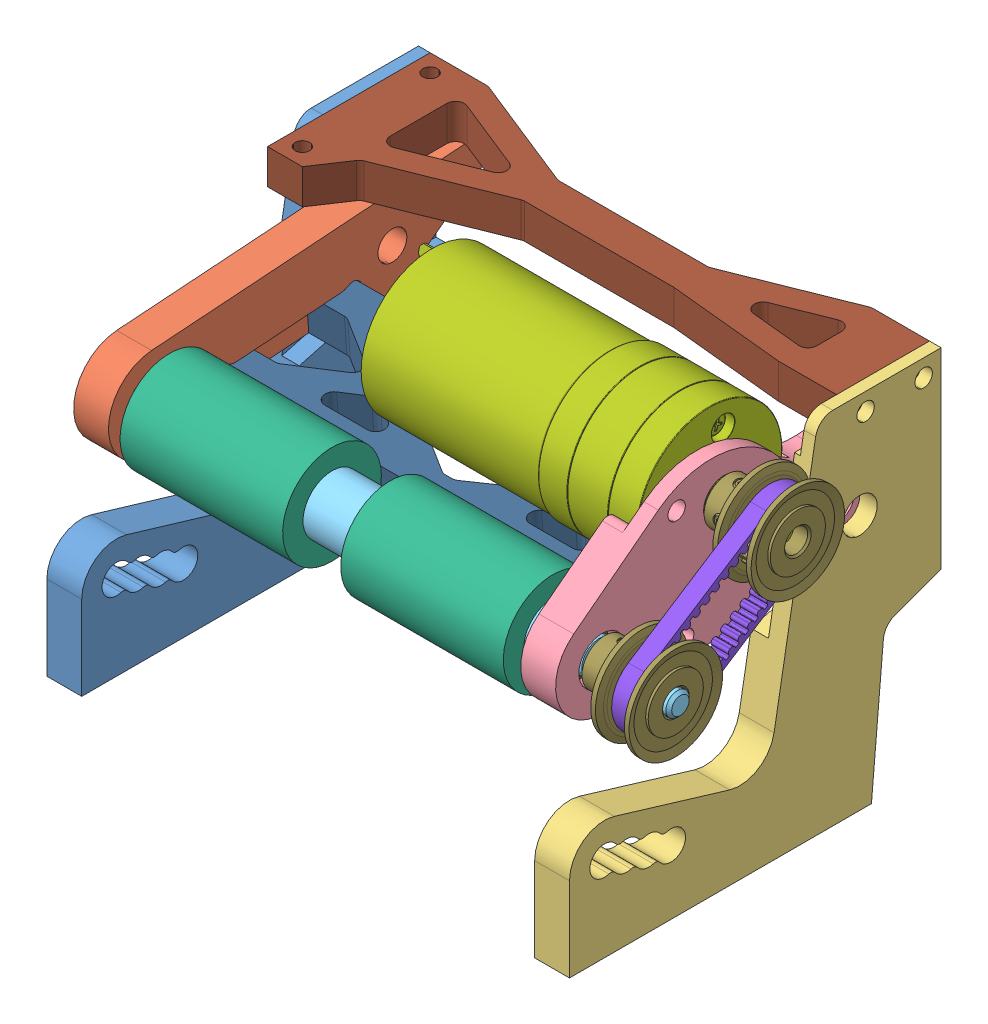
SolidWorks assembly dribblermod, configuration Default. Lengths in mm.
Overall size (177.13 177.13 177.13).
14 component instances, 12 part files, 32 mates.
Components (placement in the parent):
- dribbler_block_right-1: dribbler_block_right [Default] at (-43.6421 -1.0732 35.5028) size (6 62 64)
- dribbler_block_right_moving-1: dribbler_block_right_moving [Default] at (-40.1421 -2.5118 32.3999) x (1 0 0) z (0 -0.070885 0.997484) size (6 16 65)
- dribbler_block_left-1: dribbler_block_left [Default] at (40.3579 -1.0732 35.5028) size (6 62 64)
- dribbler_block_left_moving-1: dribbler_block_left_moving [Default] at (36.8579 -2.5118 32.3999) x (1 0 0) z (0 -0.070885 0.997484) size (6 27.29 65)
- dribbler_rod-1: dribbler_rod [Default] at (-40.1421 40.0205 26.3997) x (1 0 0) z (0 -0.512667 0.858587) size (96.5 10 10)
- dribbler_roll-1: dribbler_roll [Default] at (1.3579 40.0205 26.3997) x (1 0 0) z (0 -0.953057 0.30279) size (74.91 74.91 74.91)
- pololu_25D_motor_enc-1: pololu_25D_motor_enc [Default] at (35.3579 53.5449 5.3738) x (0 0.27455 0.961573) z (1 0 0) size (72.45 72.45 72.45)
- timing_belt_43_bent-3: timing_belt_43_bent [Default] at (50.7579 40.0205 26.3997) x (1 0 0) z (0 -0.540978 0.841037) size (39.64 39.64 39.64)
- MR106ZZ-1: MR106ZZ [Default] at (-34.1421 40.0205 26.3997) x (-1 0 0) z (0 0.924225 0.381849) size (3 10 10)
- MR106ZZ-2: MR106ZZ [Default] at (36.8579 40.0205 26.3997) x (1 0 0) z (0 -0.20056 0.979681) size (3 10 10)
- dribbler_block_support_moving-1: dribbler_block_support_moving [Default] at (-37.1421 32.8203 14.8603) x (1 0 0) z (0 -0.070885 0.997484) size (77 6 24)
- dribbler_block_support-2: dribbler_block_support [Default] at (-41.6421 54.9268 -28.4972) size (86 6 28)
- timing_pulley_18-1: timing_pulley_18 [Default] at (48.9579 40.0205 26.3997) x (0 0.966288 -0.257463) z (-1 0 0) size (16.1 16.1 12.2)
- timing_pulley_18-2: timing_pulley_18 [Default] at (48.9579 53.5449 5.3738) x (0 0 1) z (-1 0 0) size (16.1 16.1 12.2)
Mates (geometry in assembly coordinates):
- Concentric1: concentric aligned: cylinder of dribbler_block_right-1 through (-37.6421 42.9268 -14.4972) axis (-1 0 0) radius 3; cylinder of dribbler_block_right_moving-1 through (-34.1421 42.9268 -14.4972) axis (-1 0 0) radius 2.5
- Concentric2: concentric anti-aligned: cylinder of dribbler_rod-1 through (56.3579 40.0205 26.3997) axis (1 0 0) radius 5; cylinder of dribbler_roll-1 through (34.3579 40.0205 26.3997) axis (-1 0 0) radius 5
- Width1: width anti-aligned: plane of dribbler_rod-1 through (36.3579 44.3134 28.963) normal (1 0 0); plane of dribbler_rod-1 through (-33.6421 43.0255 28.194) normal (-1 0 0); plane of dribbler_roll-1 through (-31.6421 40.0205 26.3997) normal (-1 0 0); plane of dribbler_roll-1 through (34.3579 40.0205 26.3997) normal (1 0 0)
- Concentric9: concentric aligned: cylinder of dribbler_block_left-1 through (46.3579 42.9268 -14.4972) axis (-1 0 0) radius 3; cylinder of dribbler_block_left_moving-1 through (42.8579 42.9268 -14.4972) axis (-1 0 0) radius 2.5
- Coincident13: coincident anti-aligned: plane of dribbler_block_left_moving-1 through (40.3579 50.1545 -8.261) normal (-1 0 0); plane of pololu_25D_motor_enc-1 through (40.3579 53.5449 5.3738) normal (1 0 0)
- Concentric15: concentric aligned: cylinder of dribbler_block_left_moving-1 through (42.8579 53.5449 5.3738) axis (-1 0 0) radius 3.55; cylinder of pololu_25D_motor_enc-1 through (42.8579 53.5449 5.3738) axis (-1 0 0) radius 3.5
- Concentric16: concentric anti-aligned: cylinder of pololu_25D_motor_enc-1 through (32.8579 55.8786 13.5471) axis (1 0 0) radius 1.35; cylinder of dribbler_block_left_moving-1 through (42.8579 55.8786 13.5471) axis (-1 0 0) radius 1.5
- Width3: width anti-aligned: plane of dribbler_block_right_moving-1 through (-40.1421 40.0205 26.3997) normal (-1 0 0); plane of dribbler_block_left_moving-1 through (42.8579 40.0205 26.3997) normal (1 0 0); plane of dribbler_block_right-1 through (-40.6421 -1.0732 35.5028) normal (1 0 0); plane of dribbler_block_left-1 through (43.3579 -1.0732 35.5028) normal (-1 0 0)
- Concentric31: concentric anti-aligned: cylinder of dribbler_block_right_moving-1 through (-34.1421 40.0205 26.3997) axis (-1 0 0) radius 4; cylinder of MR106ZZ-1 through (-34.1421 40.0205 26.3997) axis (1 0 0) radius 5
- Concentric32: concentric aligned: cylinder of dribbler_block_left_moving-1 through (42.8579 40.0205 26.3997) axis (-1 0 0) radius 4; cylinder of MR106ZZ-2 through (36.8579 40.0205 26.3997) axis (-1 0 0) radius 5
- Concentric33: concentric aligned: cylinder of dribbler_rod-1 through (56.3579 40.0205 26.3997) axis (1 0 0) radius 3; cylinder of MR106ZZ-1 through (-34.1421 40.0205 26.3997) axis (1 0 0) radius 3
- Concentric34: concentric anti-aligned: cylinder of dribbler_rod-1 through (56.3579 40.0205 26.3997) axis (1 0 0) radius 3; cylinder of MR106ZZ-2 through (36.8579 40.0205 26.3997) axis (-1 0 0) radius 3
- Coincident32: coincident anti-aligned: plane of dribbler_rod-1 through (-34.1421 42.5962 27.9377) normal (-1 0 0); plane of MR106ZZ-1 through (-34.1421 38.8749 29.1724) normal (1 0 0)
- Coincident33: coincident anti-aligned: plane of dribbler_rod-1 through (36.8579 43.0255 28.194) normal (1 0 0); plane of MR106ZZ-2 through (36.8579 42.9595 27.0014) normal (-1 0 0)
- Coincident34: coincident anti-aligned: plane of dribbler_block_right_moving-1 through (-37.1421 -2.5118 32.3999) normal (1 0 0); plane of dribbler_block_support_moving-1 through (-37.1421 38.8052 15.2856) normal (-1 0 0)
- Concentric35: concentric anti-aligned: cylinder of dribbler_block_right_moving-1 through (-40.1431 36.0255 12.0805) axis (1 0 0) radius 1.5; cylinder of dribbler_block_support_moving-1 through (-37.1421 36.0255 12.0805) axis (-1 0 0) radius 1.25
- Concentric36: concentric anti-aligned: cylinder of dribbler_block_right_moving-1 through (-40.1431 37.3014 -5.8743) axis (1 0 0) radius 1.5; cylinder of dribbler_block_support_moving-1 through (-37.1421 37.3014 -5.8743) axis (-1 0 0) radius 1.25
- Coincident36: coincident aligned: plane of dribbler_block_right-1 through (-37.6421 -1.0732 35.5028) normal (0 -1 0); plane of dribbler_block_left-1 through (46.3579 -1.0732 35.5028) normal (0 -1 0)
- Distance2: distance = 78 mm anti-aligned: plane of dribbler_block_right-1 through (-37.6421 60.9268 35.5028) normal (1 0 0); plane of dribbler_block_left-1 through (40.3579 60.9268 35.5028) normal (-1 0 0)
- Coincident40: coincident aligned: plane of dribbler_block_right-1 through (-37.6421 -1.0732 -28.4972) normal (0 0 -1); plane of dribbler_block_support-2 through (-31.6421 60.9268 -28.4972) normal (0 0 -1)
- Coincident41: coincident anti-aligned: plane of dribbler_block_support-2 through (-41.6421 60.9268 -0.4972) normal (-1 0 0); plane of dribbler_block_right-1 through (-41.6421 -1.0732 35.5028) normal (1 0 0)
- Concentric37: concentric anti-aligned: cylinder of dribbler_block_right-1 through (-43.6431 57.9268 -20.4972) axis (1 0 0) radius 1.5; cylinder of dribbler_block_support-2 through (-41.6421 57.9268 -20.4972) axis (-1 0 0) radius 1.25
- Concentric39: concentric anti-aligned: cylinder of dribbler_block_left-1 through (46.3589 57.9268 -15.4972) axis (-1 0 0) radius 1.5; cylinder of dribbler_block_support-2 through (44.3579 57.9268 -15.4972) axis (1 0 0) radius 1.25
- Concentric40: concentric aligned: cylinder of dribbler_rod-1 through (56.3579 40.0205 26.3997) axis (1 0 0) radius 2; cylinder of timing_pulley_18-1 through (43.0779 40.0205 26.3997) axis (1 0 0) radius 2
- Distance3: distance = 0.5 mm anti-aligned: plane of dribbler_block_left_moving-1 through (42.8579 40.0205 26.3997) normal (1 0 0); plane of timing_pulley_18-1 through (43.3579 40.0205 26.3997) normal (-1 0 0)
- Coincident43: coincident aligned: plane of timing_pulley_18-1 through (43.3579 40.0205 26.3997) normal (-1 0 0); plane of timing_pulley_18-2 through (43.3579 53.5449 5.3738) normal (-1 0 0)
- Concentric41: concentric anti-aligned: cylinder of pololu_25D_motor_enc-1 through (52.8579 53.5449 5.3738) axis (-1 0 0) radius 2; cylinder of timing_pulley_18-2 through (43.0779 53.5449 5.3738) axis (1 0 0) radius 2
- Concentric42: concentric aligned: circle of timing_belt_43_bent-3; circle of timing_pulley_18-1
- Concentric43: concentric aligned: circle of timing_belt_43_bent-3; circle of timing_pulley_18-2
- Width4: width aligned: plane of timing_belt_43_bent-3 through (53.7579 40.0205 26.3997) normal (1 0 0); plane of timing_belt_43_bent-3 through (50.7579 40.0205 26.3997) normal (-1 0 0); plane of timing_pulley_18-1 through (50.2079 40.0205 26.3997) normal (1 0 0); plane of timing_pulley_18-1 through (54.3079 40.0205 26.3997) normal (-1 0 0)
- Coincident44: coincident anti-aligned: plane of dribbler_block_left_moving-1 through (39.8579 40.0205 26.3997) normal (-1 0 0); plane of MR106ZZ-2 through (39.8579 44.9189 27.4025) normal (1 0 0)
- Coincident45: coincident anti-aligned: plane of dribbler_block_right_moving-1 through (-37.1421 40.0205 26.3997) normal (1 0 0); plane of MR106ZZ-1 through (-37.1421 38.1112 31.0208) normal (-1 0 0)
